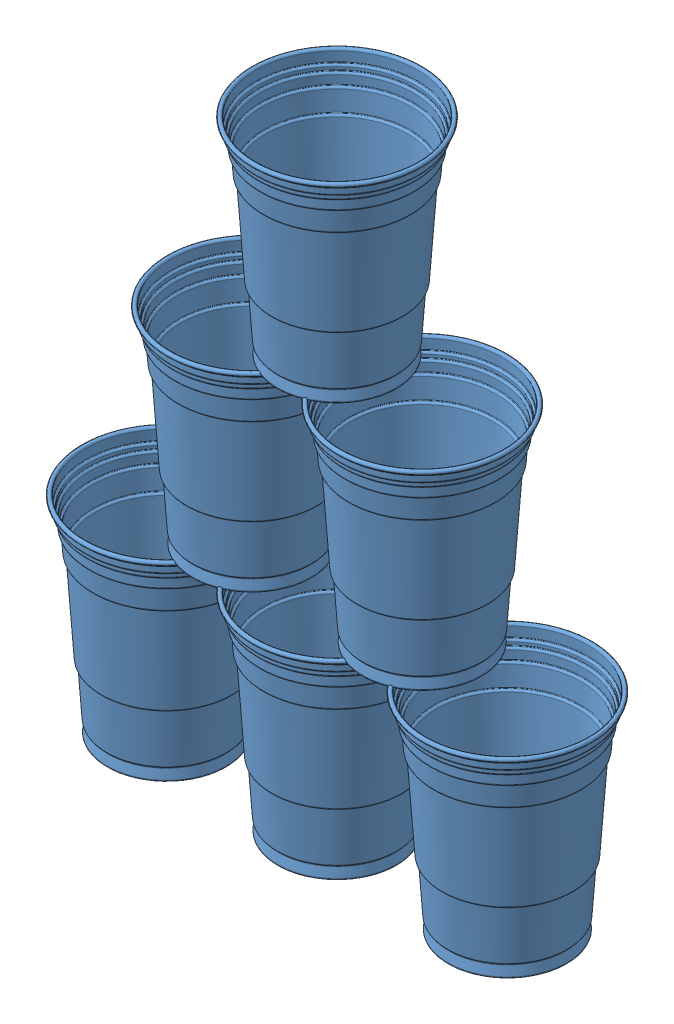
SolidWorks assembly Assem1, configuration Default. Lengths in mm.
Overall size (298.67 363.22 99.54).
6 component instances, 1 part files, 12 mates.
Components (placement in the parent):
- 16oz. Red Solo Cup-1: 16oz. Red Solo Cup [Default] at origin size (99.54 121.92 99.54)
- 16oz. Red Solo Cup-2: 16oz. Red Solo Cup [Default] at (0 241.3 0) size (99.54 121.92 99.54)
- 16oz. Red Solo Cup-3: 16oz. Red Solo Cup [Default] at (99.568 0 0) size (99.54 121.92 99.54)
- 16oz. Red Solo Cup-4: 16oz. Red Solo Cup [Default] at (-99.568 0 0) size (99.54 121.92 99.54)
- 16oz. Red Solo Cup-5: 16oz. Red Solo Cup [Default] at (-49.784 120.65 0) size (99.54 121.92 99.54)
- 16oz. Red Solo Cup-6: 16oz. Red Solo Cup [Default] at (49.784 120.65 0) size (99.54 121.92 99.54)
Mates (geometry in assembly coordinates):
- Coincident1: coincident aligned: plane of 16oz. Red Solo Cup-1 through (0 0 0) normal (0 1 0); plane of assembly through (0 0 0) normal (0 1 0)
- Coincident2: coincident aligned: plane of 16oz. Red Solo Cup-1 through (0 0 0) normal (1 0 0); plane of assembly through (0 0 0) normal (1 0 0)
- Coincident3: coincident aligned: plane of 16oz. Red Solo Cup-1 through (0 0 0) normal (0 0 1); plane of assembly through (0 0 0) normal (0 0 1)
- Coincident4: coincident aligned: plane of 16oz. Red Solo Cup-1 through (0 0 0) normal (0 0 1); plane of 16oz. Red Solo Cup-3 through (99.568 0 0) normal (0 0 1)
- Coincident5: coincident aligned: plane of 16oz. Red Solo Cup-1 through (0 0 0) normal (0 1 0); plane of 16oz. Red Solo Cup-3 through (99.568 0 0) normal (0 1 0)
- Distance1: distance = 99.568 mm aligned: plane of 16oz. Red Solo Cup-3 through (99.568 0 0) normal (1 0 0); plane of assembly through (0 0 0) normal (1 0 0)
- Distance2: distance = 120.65 mm aligned: plane of 16oz. Red Solo Cup-5 through (-49.784 120.65 0) normal (0 1 0); plane of 16oz. Red Solo Cup-4 through (-99.568 0 0) normal (0 1 0)
- Coincident8: coincident aligned: plane of 16oz. Red Solo Cup-5 through (-49.784 120.65 0) normal (0 0 1); plane of assembly
- Distance3: distance = 49.784 mm aligned: plane of 16oz. Red Solo Cup-5 through (-49.784 120.65 0) normal (1 0 0); plane of assembly
- Coincident10: coincident aligned: plane of 16oz. Red Solo Cup-5 through (-49.784 120.65 0) normal (0 1 0); plane of 16oz. Red Solo Cup-6 through (49.784 120.65 0) normal (0 1 0)
- Coincident11: coincident aligned: plane of 16oz. Red Solo Cup-6 through (49.784 120.65 0) normal (0 0 1); plane of assembly
- Distance4: distance = 49.784 mm aligned: plane of 16oz. Red Solo Cup-6 through (49.784 120.65 0) normal (1 0 0); plane of assembly
